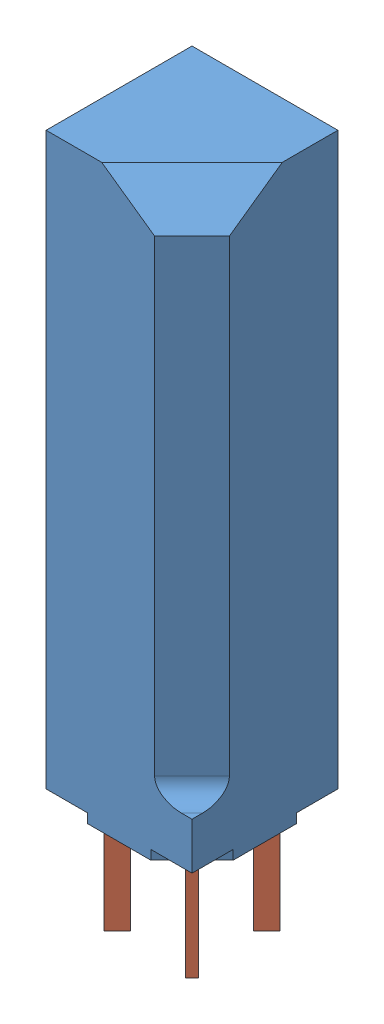
SolidWorks assembly Assem1, configuration Default. Lengths in mm.
Overall size (3.9 18.45 3.9).
5 component instances, 2 part files, 4 mates.
Components (placement in the parent):
- Body-1: Body [Default] at origin size (3.9 15.5 3.9)
- Pin-1: Pin [Default] at (-1 -2.95 1) x (0.707107 0 -0.707107) z (0.707107 0 0.707107) size (0.5 3.2 0.25)
- Pin-2: Pin [Default] at (1 -2.95 1) x (-0.707107 0 -0.707107) z (0.707107 0 -0.707107) size (0.5 3.2 0.25)
- Pin-3: Pin [Default] at (1 -2.95 -1) x (-0.707107 0 0.707107) z (-0.707107 0 -0.707107) size (0.5 3.2 0.25)
- Pin-4: Pin [Default] at (-1 -2.95 -1) x (0.707107 0 0.707107) z (-0.707107 0 0.707107) size (0.5 3.2 0.25)
Mates (geometry in assembly coordinates):
- Coincident1: coincident: plane of Body-1 through (0 0 0) normal (0.707107 0 0.707107); line of Pin-1 through (-1 0.41 1) axis (0 -1 0)
- Parallel1: parallel aligned: plane of Body-1 through (0 0 0) normal (0.707107 0 0.707107); plane of Pin-1 through (-1.0884 0.25 1.2652) normal (0.707107 0 0.707107)
- Coincident3: coincident anti-aligned: plane of Body-1 through (0 0.25 0) normal (0 -1 0); plane of Pin-1 through (-1 0.25 1) normal (0 1 0)
- Distance1: distance = 1.4142 mm: line of Body-1 through (16.775 0 -0.5125) axis (0 0 1); line of Pin-1 through (-1 0.41 1) axis (0 -1 0)
